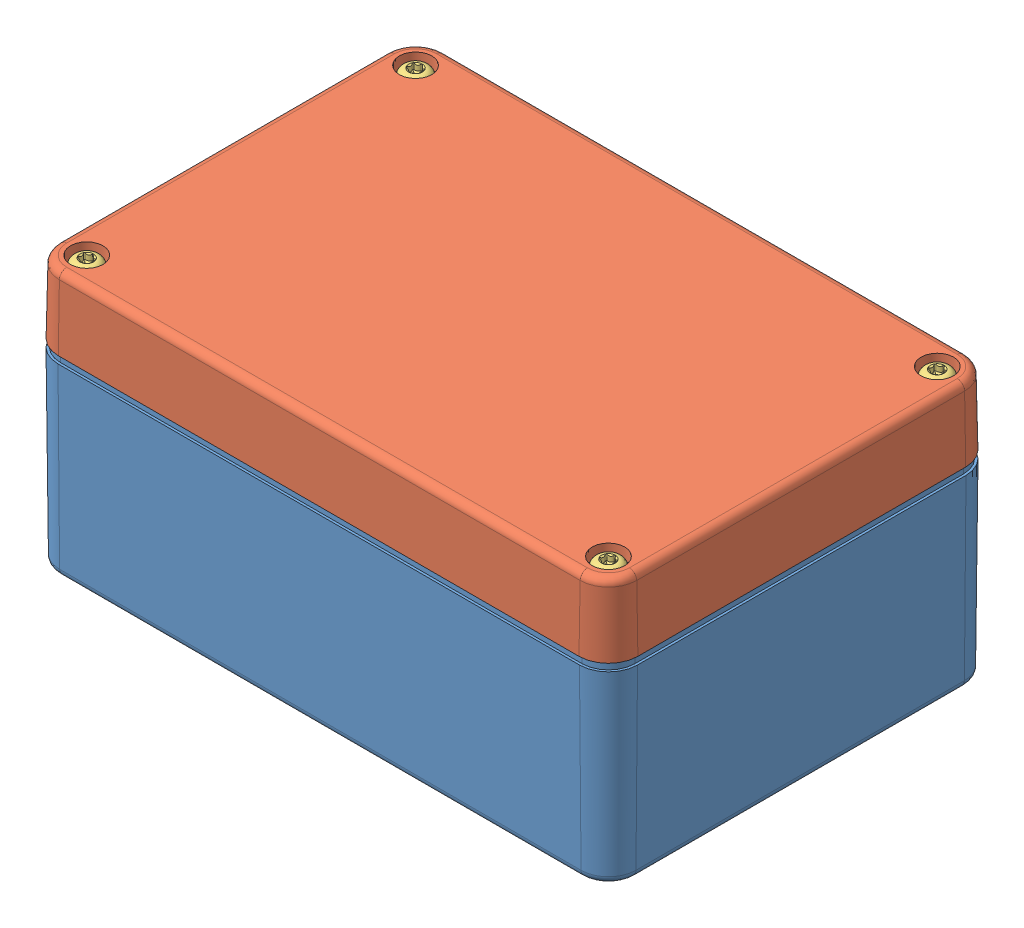
SolidWorks assembly serpac_tx2_enclosure, configuration Default. Lengths in mm.
Overall size (119.96 54.5 80.01).
15 component instances, 6 part files, 0 mates.
Components (placement in the parent):
- RB53X16Y_RevB(Default)-1: RB53X16Y_RevB(Default) [Default] at origin size (119.96 42.04 80.01)
- RB53-X06Y_RevB-1: RB53-X06Y_RevB [Default] x (-1 0 0) z (0 0 1) size (119.99 14.99 80.06) (hidden)
- 6023_Pan_Head_screw_torx_head-4-40_Rev_B-2-1: 6023_Pan_Head_screw_torx_head-4-40_Rev_B-2 [Default] at (54.0004 -12.954 34.036) x (1 0 0) z (0 1 0) size (5.56 5.56 27.69)
- 6023_Pan_Head_screw_torx_head-4-40_Rev_B-2-2: 6023_Pan_Head_screw_torx_head-4-40_Rev_B-2 [Default] at (-54.0004 -12.954 34.036) x (1 0 0) z (0 1 0) size (5.56 5.56 27.69)
- 6023_Pan_Head_screw_torx_head-4-40_Rev_B-2-3: 6023_Pan_Head_screw_torx_head-4-40_Rev_B-2 [Default] at (54.0004 -12.954 -34.036) x (1 0 0) z (0 1 0) size (5.56 5.56 27.69)
- 6023_Pan_Head_screw_torx_head-4-40_Rev_B-2-4: 6023_Pan_Head_screw_torx_head-4-40_Rev_B-2 [Default] at (-54.0004 -12.954 -34.036) x (1 0 0) z (0 1 0) size (5.56 5.56 27.69)
- 6102_4-40_threaded insert-2-1: 6102_4-40_threaded insert-2 [Default] at (-54.0004 -6.096 -34.036) x (-0.837169 0 -0.546944) z (-0.546944 0 0.837169) size (5.82 5.08 5.82)
- 6102_4-40_threaded insert-2-2: 6102_4-40_threaded insert-2 [Default] at (54.0004 -6.096 -34.036) x (-0.837169 0 -0.546944) z (-0.546944 0 0.837169) size (5.82 5.08 5.82)
- 6102_4-40_threaded insert-2-3: 6102_4-40_threaded insert-2 [Default] at (-54.0004 -6.096 34.036) x (-0.837169 0 -0.546944) z (-0.546944 0 0.837169) size (5.82 5.08 5.82)
- 6102_4-40_threaded insert-2-4: 6102_4-40_threaded insert-2 [Default] at (54.0004 -6.096 34.036) x (-0.837169 0 -0.546944) z (-0.546944 0 0.837169) size (5.82 5.08 5.82)
- 6022 #10-16 HL Pan HD-2-1: 6022 #10-16 HL Pan HD-2 [Default] at (40.7416 -32.004 -29.0068) x (1 0 0) z (0 1 0) size (8.18 8.18 9.67)
- 6022 #10-16 HL Pan HD-2-2: 6022 #10-16 HL Pan HD-2 [Default] at (-40.7416 -32.004 29.0068) x (1 0 0) z (0 1 0) size (8.18 8.18 9.67)
- 6022 #10-16 HL Pan HD-2-3: 6022 #10-16 HL Pan HD-2 [Default] at (40.7416 -32.004 29.0068) x (1 0 0) z (0 1 0) size (8.18 8.18 9.67)
- 6022 #10-16 HL Pan HD-2-4: 6022 #10-16 HL Pan HD-2 [Default] at (-40.7416 -32.004 -29.0068) x (1 0 0) z (0 1 0) size (8.18 8.18 9.67) (hidden)
- RB53 O Ring Rev A-1: RB53 O Ring Rev A [Default] at (0 1.4224 0) size (117.3 2.29 77.27)
